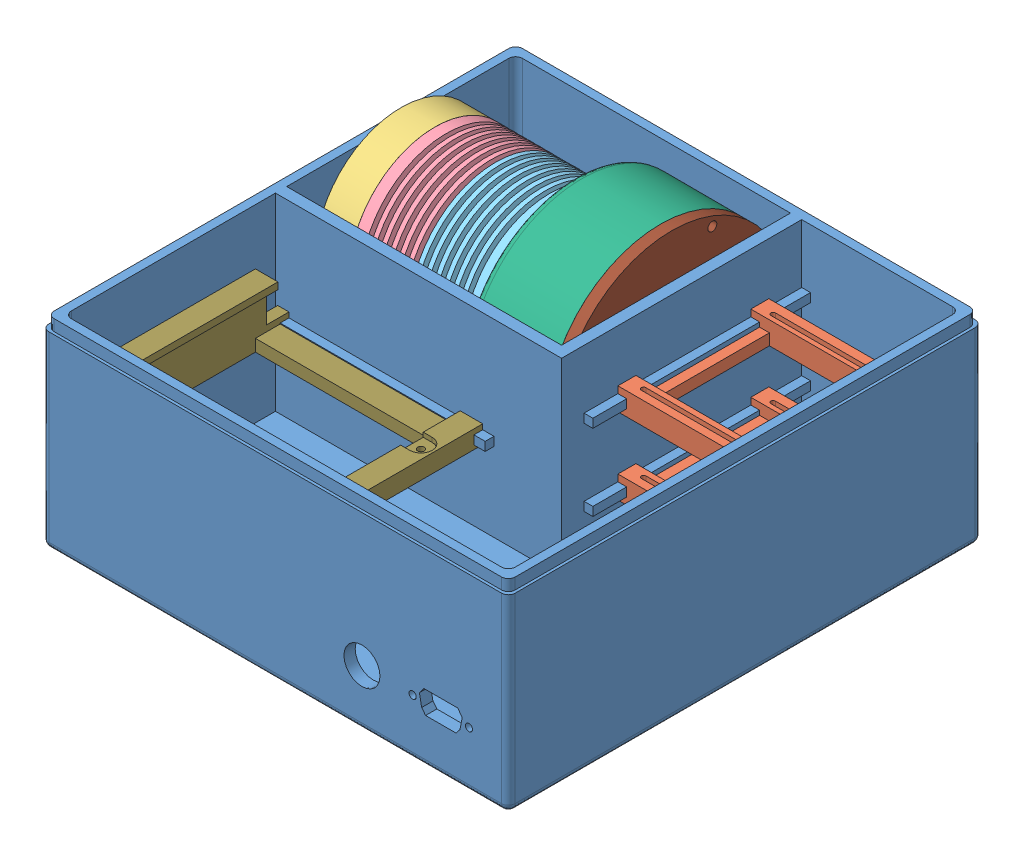
SolidWorks assembly Assemblage boitier de transport, configuration Défaut. Lengths in mm.
Overall size (207 132.77 220.78).
15 component instances, 13 part files, 14 mates.
Components (placement in the parent):
- boite de rangement-1: boite de rangement [Défaut] at (-2.7643 -43.7222 0) size (207 88.9 210.2)
- support des petits PCB-1: support des petits PCB [Défaut] at (60.6357 12.0778 -52) size (70 10 67)
- support des petits PCB-2: support des petits PCB [Défaut] at (60.6357 -21.8222 -52) size (70 10 67)
- Assemblage version 2-1: Assemblage version 2 [Défaut] at (-17.5643 11.7745 -43.1341) x (0 0 1) z (-1 0 0) size (132.77 132.77 120.1)
  - pièce de support de lentille V.0.3-1: pièce de support de lentille V.0.3 [Défaut] at (-29.1782 -8.1326 68.7) size (76.2 76.2 15)
  - pièce no1 avec ailettes V.0.3-1: pièce no1 avec ailettes V.0.3 [Défaut] at (17.5136 -29.3675 68.7) x (-1 0 0) z (0 0 -1) size (76.2 76.2 27)
  - pièce no2 milieu avec trous aluminium V.0.3-1: pièce no2 milieu avec trous aluminium V.0.3 [Défaut] at (-37.9058 -14.3155 6.7) size (76.2 76.2 35)
  - support PCB-1: support PCB [Défaut] at (-6.1659 0.3032 -31.4) size (101.6 101.6 38.84)
  - LC2679-Solidworks-1: LC2679-Solidworks [Default] at (-6.1659 0.3032 70.5942) size (25.4 25.4 7.26)
  - NE2R30B-Solidworks-1: NE2R30B-Solidworks [Default] at (-6.1659 0.3032 37.755) x (0 0 -1) z (1 0 0) size (2.11 50.8 50.8)
  - pièce imprimé 3D_intersection V.0.2-1: pièce imprimé 3D_intersection V.0.2 [Défaut] at (-22.7911 -6.8055 -3.3) size (50.8 50.8 35)
  - pièce imprimé 3D_socket-1: pièce imprimé 3D_socket [Défaut] at (-22.7911 -6.8055 -8.3) size (50.8 50.8 10)
  - embout avec logo-1: embout avec logo [Défaut] at (-6.1659 0.3032 -31.4) x (-0.923728 -0.383049 0) z (0 0 -1) size (101.6 101.6 5)
- support de DAC-2: support de DAC [Défaut] at (-57.2643 -5.5222 53.15) x (-1 0 0) z (0 0 -1) size (91 27 93.5)
- Couvercle-1: Couvercle [Défaut] at (-2.7643 40.1778 0) size (207 23.86 210.2) (hidden)
Mates (geometry in assembly coordinates):
- Coïncidente4: coincident anti-aligned: plane of boite de rangement-1 through (29.6357 -18.7222 12.0154) normal (1 0 0); plane of support des petits PCB-2 through (29.6357 -14.8222 -85.5) normal (-1 0 0)
- Coïncidente5: coincident anti-aligned: plane of boite de rangement-1 through (25.7357 -14.8222 12.0154) normal (0 1 0); plane of support des petits PCB-2 through (25.6357 -14.8222 -85.5) normal (0 -1 0)
- Distance2: distance = 15 mm aligned: plane of support des petits PCB-2 through (25.6357 -11.8222 -18.5) normal (0 0 1); plane of boite de rangement-1 through (-2.7643 -43.7222 -3.5) normal (0 0 1)
- Coïncidente7: coincident anti-aligned: plane of boite de rangement-1 through (25.7357 19.0778 12.0154) normal (0 1 0); plane of support des petits PCB-1 through (25.6357 19.0778 -85.5) normal (0 -1 0)
- Coïncidente8: coincident: line of boite de rangement-1 through (29.6357 19.0778 -3.5) axis (0 0 -1); plane of support des petits PCB-1 through (29.6357 19.0778 -85.5) normal (-1 0 0)
- Distance3: distance = 15 mm aligned: plane of support des petits PCB-1 through (25.6357 22.0778 -18.5) normal (0 0 1); plane of boite de rangement-1 through (-2.7643 -43.7222 -3.5) normal (0 0 1)
- Coïncidente10: coincident anti-aligned: plane of boite de rangement-1 through (-101.2643 45.1778 105.1) normal (1 0 0); plane of Assemblage version 2-1/pièce de support de lentille V.0.3-1 through (-101.2643 12.0778 -49.3) normal (-1 0 0)
- Coaxiale1: concentric anti-aligned: cylinder of boite de rangement-1 through (12.7357 12.0778 -49.3) axis (-1 0 0) radius 50.8; cylinder of Assemblage version 2-1/support PCB-1 through (-24.2643 12.0778 -49.3) axis (1 0 0) radius 50.8
- Distance4: distance = 5 mm aligned: plane of boite de rangement-1 through (-4.2643 -43.7222 0) normal (1 0 0); plane of support de DAC-2 through (-9.2643 2.4778 89.9) normal (1 0 0)
- Coïncidente12: coincident anti-aligned: plane of boite de rangement-1 through (31.2511 0.1778 100.1) normal (0 1 0); plane of support de DAC-2 through (-100.2643 0.1778 99.9) normal (0 -1 0)
- Coïncidente13: coincident anti-aligned: plane of boite de rangement-1 through (31.2511 -3.7222 10.4) normal (0 0 1); plane of support de DAC-2 through (-100.2643 -3.8222 10.4) normal (0 0 -1)
- Coïncidente14: coincident aligned: plane of boite de rangement-1 through (100.7357 45.1778 105.1) normal (1 0 0); plane of Couvercle-1 through (100.7357 64.0378 105.1) normal (1 0 0)
- Coïncidente15: coincident aligned: plane of boite de rangement-1 through (-106.2643 45.1778 105.1) normal (0 0 1); plane of Couvercle-1 through (-106.2643 64.0378 105.1) normal (0 0 1)
- Coïncidente16: coincident aligned: line of boite de rangement-1 through (100.7357 40.1778 102.1) axis (0 0 -1); line of Couvercle-1 through (100.7357 40.1778 102.1) axis (0 0 -1)
